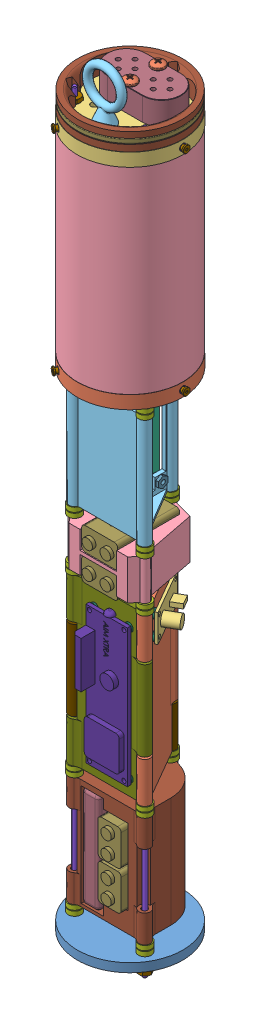
SolidWorks assembly S1B_Electronics_Bay, configuration Default. Lengths in mm.
Overall size (104.18 564.06 103.27).
130 component instances, 38 part files, 86 mates.
Components (placement in the parent):
- S1B_Electronics_Bay_Aft_Bulkhead-1: S1B_Electronics_Bay_Aft_Bulkhead [Default] at origin size (76.45 6.35 76.45)
- S1B_Electronics_Bay_Spacer_Aft_Bulkhead-1: S1B_Electronics_Bay_Spacer_Aft_Bulkhead [Default] at (0 353.8981 0) size (76.71 9.53 76.71)
- S1B_Electronics_Bay_Spacer_Forward_Bulkhead-1: S1B_Electronics_Bay_Spacer_Forward_Bulkhead [Default] at (0 506.2727 0) size (76.71 9.53 76.71)
- S1B_Fat_Bulkhead_Coupler-2: S1B_Fat_Bulkhead_Coupler [Default] at (0 363.4231 0) size (76.45 142.85 76.45)
- S1B_Electronics_Bay_3014T45_Steel Eyebolt with Shoulder - for Lifting-1: S1B_Electronics_Bay_3014T45_Steel Eyebolt with Shoulder - for Lifting [3014T45] at (0 539.6102 18.415) size (30.16 64.29 14.29)
- S1B_Electronics_Bay_90107A029_316 Stainless Steel Washer-1: S1B_Electronics_Bay_90107A029_316 Stainless Steel Washer [90107A029] at (0 505.1805 18.415) x (-1 0 0) z (0 0 -1) size (15.88 1.09 15.88)
- S1B_Electronics_Bay_95462A029_Medium-Strength Steel Hex Nut-1: S1B_Electronics_Bay_95462A029_Medium-Strength Steel Hex Nut [95462A029] at (0 502.4024 18.415) x (1 0 0) z (0 1 0) size (11.11 12.83 5.56)
- S1B_Electronics_Bay_98804A006_18-8 Stainless Steel Threaded Rod-1: S1B_Electronics_Bay_98804A006_18-8 Stainless Steel Threaded Rod [98804A006] at (0 257.975 -29.464) x (1 0 0) z (0 -1 0) size (3.17 3.17 534.7)
- S1B_Electronics_Bay_91841A006_18-8 Stainless Steel Hex Nut-1: S1B_Electronics_Bay_91841A006_18-8 Stainless Steel Hex Nut [91841A006] at (0 517.8218 -29.464) x (-1 0 0) z (0 0 -1) size (7.94 2.78 9.17)
- S1B_Electronics_Bay_90107A006_316 Stainless Steel Washer-1: S1B_Electronics_Bay_90107A006_316 Stainless Steel Washer [90107A006] at (0 515.7977 -29.464) size (7.14 0.64 7.14)
- S1B_Electronics_Bay_90107A006_316 Stainless Steel Washer-4: S1B_Electronics_Bay_90107A006_316 Stainless Steel Washer [90107A006] at (25.5166 515.7977 14.732) x (-0.5 0 0.866025) z (-0.866025 0 -0.5) size (7.14 0.64 7.14)
- S1B_Electronics_Bay_90107A006_316 Stainless Steel Washer-5: S1B_Electronics_Bay_90107A006_316 Stainless Steel Washer [90107A006] at (-25.5166 515.7977 14.732) x (-0.5 0 -0.866025) z (0.866025 0 -0.5) size (7.14 0.64 7.14)
- S1B_Electronics_Bay_91841A006_18-8 Stainless Steel Hex Nut-2: S1B_Electronics_Bay_91841A006_18-8 Stainless Steel Hex Nut [91841A006] at (25.5166 517.8218 14.732) x (0.5 0 -0.866025) z (0.866025 0 0.5) size (7.94 2.78 9.17)
- S1B_Electronics_Bay_91841A006_18-8 Stainless Steel Hex Nut-3: S1B_Electronics_Bay_91841A006_18-8 Stainless Steel Hex Nut [91841A006] at (-25.5166 517.8218 14.732) x (0.5 0 0.866025) z (-0.866025 0 0.5) size (7.94 2.78 9.17)
- S1B_Electronics_Bay_98804A006_18-8 Stainless Steel Threaded Rod-4: S1B_Electronics_Bay_98804A006_18-8 Stainless Steel Threaded Rod [98804A006] at (25.5166 257.975 14.732) x (-0.5 0 0.866025) z (0 -1 0) size (3.17 3.17 534.7)
- S1B_Electronics_Bay_98804A006_18-8 Stainless Steel Threaded Rod-5: S1B_Electronics_Bay_98804A006_18-8 Stainless Steel Threaded Rod [98804A006] at (-25.5166 257.975 14.732) x (-0.5 0 -0.866025) z (0 -1 0) size (3.17 3.17 534.7)
- S1B_Electronics_Bay_90107A006_316 Stainless Steel Washer-12: S1B_Electronics_Bay_90107A006_316 Stainless Steel Washer [90107A006] at (0 0 -29.464) x (1 0 0) z (0 0 -1) size (7.14 0.64 7.14)
- S1B_Electronics_Bay_91841A006_18-8 Stainless Steel Hex Nut-14: S1B_Electronics_Bay_91841A006_18-8 Stainless Steel Hex Nut [91841A006] at (0 -2.0241 -29.464) x (-1 0 0) z (0 0 1) size (7.94 2.78 9.17)
- S1B_Electronics_Bay_90107A006_316 Stainless Steel Washer-13: S1B_Electronics_Bay_90107A006_316 Stainless Steel Washer [90107A006] at (25.5166 0 14.732) x (-0.5 0 0.866025) z (0.866025 0 0.5) size (7.14 0.64 7.14)
- S1B_Electronics_Bay_90107A006_316 Stainless Steel Washer-14: S1B_Electronics_Bay_90107A006_316 Stainless Steel Washer [90107A006] at (-25.5166 0 14.732) x (-0.5 0 -0.866025) z (-0.866025 0 0.5) size (7.14 0.64 7.14)
- S1B_Electronics_Bay_91841A006_18-8 Stainless Steel Hex Nut-15: S1B_Electronics_Bay_91841A006_18-8 Stainless Steel Hex Nut [91841A006] at (25.5166 -2.0241 14.732) x (0.5 0 -0.866025) z (-0.866025 0 -0.5) size (7.94 2.78 9.17)
- S1B_Electronics_Bay_91841A006_18-8 Stainless Steel Hex Nut-16: S1B_Electronics_Bay_91841A006_18-8 Stainless Steel Hex Nut [91841A006] at (-25.5166 -2.0241 14.732) x (0.5 0 0.866025) z (0.866025 0 -0.5) size (7.94 2.78 9.17)
- S1B_Electronics_Bay_Avionics_Stack-1: S1B_Electronics_Bay_Avionics_Stack [Default] at (8.2928 -12.2914 -69.8691) size (104.18 344.14 103.27)
  - S1B_Flight_Power_Stack_Assy-1: S1B_Flight_Power_Stack_Assy [Default] at (-4.2933 16.5157 -11.6983) size (58.99 80 57.67)
    - S1B_Power_Stack-1: S1B_Power_Stack [Default] at (-4.1095 89.1616 81.6309) size (58.99 80 52.18)
    - S1B_9V Battery-1: S1B_9V Battery [Default] at (-5.5953 51.787 105.8736) x (0 0 -1) z (0 -1 0) size (47.57 16.87 26.11)
    - S1B_LiPo_A1-1: S1B_LiPo_A1 [Default] at (-22.7297 11.3191 64.2994) x (0 1 0) z (0 0 -1) size (72.97 12.27 33.73)
    - S1B_9V Battery-2: S1B_9V Battery [Default] at (-5.5953 23.6758 105.8736) x (0 0 -1) z (0 -1 0) size (47.57 16.87 26.11)
  - S1B_Fight_Computer_Stack_Assy-1: S1B_Fight_Computer_Stack_Assy [Default] at (37.1119 269.2904 8.8488) x (0.5 0 0.866025) z (0 -1 0) size (74.68 77.18 120)
    - S1B_6.86mm_Nut_3mm_Hole-7: S1B_6.86mm_Nut_3mm_Hole [Default] at (49.4605 62.5264 50.3494) x (0.433013 -0.75 0.5) z (-0.25 0.433013 0.866025) size (7.92 1.91 6.86)
    - S1B_6.86mm_Nut_3mm_Hole-10: S1B_6.86mm_Nut_3mm_Hole [Default] at (38.5881 85.168 145.066) x (-0.433013 0.75 -0.5) z (-0.25 0.433013 0.866025) size (7.92 1.91 6.86)
    - S1B_6.86mm_Nut_3mm_Hole-11: S1B_6.86mm_Nut_3mm_Hole [Default] at (36.9383 84.2155 50.3494) x (0.433013 -0.75 -0.5) z (0.25 -0.433013 0.866025) size (7.92 1.91 6.86)
    - S1B_6.86mm_Nut_3mm_Hole-12: S1B_6.86mm_Nut_3mm_Hole [Default] at (49.4605 62.5264 145.066) x (0.433013 -0.75 -0.5) z (0.25 -0.433013 0.866025) size (7.92 1.91 6.86)
    - S1B_Ruber_Washer_3mm-5: S1B_Ruber_Washer_3mm [Default] at (53.7083 64.9789 145.066) x (-0.5 0.866025 0) z (0 0 1) size (6 1.25 6)
    - S1B_Ruber_Washer_3mm-6: S1B_Ruber_Washer_3mm [Default] at (41.1861 86.668 145.066) x (-0.5 0.866025 0) z (0 0 1) size (6 1.25 6)
    - S1B_Ruber_Washer_3mm-7: S1B_Ruber_Washer_3mm [Default] at (53.7083 64.9789 50.3494) x (-0.5 0.866025 0) z (0 0 1) size (6 1.25 6)
    - S1B_Ruber_Washer_3mm-8: S1B_Ruber_Washer_3mm [Default] at (41.1861 86.668 50.3494) x (-0.5 0.866025 0) z (0 0 1) size (6 1.25 6)
    - S1B_Avionics_Stack - AIM-1: S1B_Avionics_Stack - AIM [Default] at (55.5493 84.6273 26.5774) x (-0.5 -0.866025 0) z (0 0 1) size (33.58 52.18 120)
    - S1B_AimXtra-1: S1B_AimXtra [Default] at (39.9161 88.8677 47.8094) x (0 0 1) z (-0.5 0.866025 0) size (102.34 16.13 30.12)
    - S1B_6.86mm_Nut_3mm_Hole-13: S1B_6.86mm_Nut_3mm_Hole [Default] at (13.2223 66.1787 125.5587) x (0.433013 0.75 -0.5) z (0.25 0.433013 0.866025) size (7.92 1.91 6.86)
    - S1B_6.86mm_Nut_3mm_Hole-14: S1B_6.86mm_Nut_3mm_Hole [Default] at (24.7223 86.0973 125.5587) x (0.433013 0.75 -0.5) z (0.25 0.433013 0.866025) size (7.92 1.91 6.86)
    - S1B_6.86mm_Nut_3mm_Hole-15: S1B_6.86mm_Nut_3mm_Hole [Default] at (13.2223 66.1787 69.0624) x (0.433013 0.75 0.5) z (-0.25 -0.433013 0.866025) size (7.92 1.91 6.86)
    - S1B_6.86mm_Nut_3mm_Hole-16: S1B_6.86mm_Nut_3mm_Hole [Default] at (24.7223 86.0973 67.5587) x (0.433013 0.75 -0.5) z (0.25 0.433013 0.866025) size (7.92 1.91 6.86)
    - S1B_Ruber_Washer_3mm-9: S1B_Ruber_Washer_3mm [Default] at (21.3404 88.0498 67.5587) x (0.5 0.866025 0) z (0 0 1) size (6 1.25 6)
    - S1B_Ruber_Washer_3mm-10: S1B_Ruber_Washer_3mm [Default] at (9.8404 68.1312 69.0624) x (0.5 0.866025 0) z (0 0 1) size (6 1.25 6)
    - S1B_Ruber_Washer_3mm-11: S1B_Ruber_Washer_3mm [Default] at (21.3404 88.0498 125.5587) x (0.5 0.866025 0) z (0 0 1) size (6 1.25 6)
    - S1B_Ruber_Washer_3mm-12: S1B_Ruber_Washer_3mm [Default] at (9.8404 68.1312 125.5587) x (0.5 0.866025 0) z (0 0 1) size (6 1.25 6)
    - S1B_Avionics_Stack-1: S1B_Avionics_Stack [Default] at (4.7361 84.6273 26.5774) size (33.58 52.18 120)
    - S1B_RBP2W-1: S1B_RBP2W [Default] at (13.9471 81.3442 101.7819) x (0 0 -1) z (0.5 0.866025 0) size (65 5.1 31.05)
    - S1B_6.86mm_Nut_3mm_Hole-17: S1B_6.86mm_Nut_3mm_Hole [Default] at (44.7248 57.1953 44.9616) x (-0.868623 0 -0.495473) z (-0.495473 0 0.868623) size (7.92 1.91 6.86)
    - S1B_6.86mm_Nut_3mm_Hole-18: S1B_6.86mm_Nut_3mm_Hole [Default] at (44.7248 57.1953 59.1316) x (-0.868623 0 -0.495473) z (-0.495473 0 0.868623) size (7.92 1.91 6.86)
    - S1B_6.86mm_Nut_3mm_Hole-19: S1B_6.86mm_Nut_3mm_Hole [Default] at (12.4948 57.1953 59.1316) x (-0.868623 0 -0.495473) z (-0.495473 0 0.868623) size (7.92 1.91 6.86)
    - S1B_6.86mm_Nut_3mm_Hole-20: S1B_6.86mm_Nut_3mm_Hole [Default] at (12.4948 57.1953 44.9616) x (-0.855922 0 -0.517105) z (-0.517105 0 0.855922) size (7.92 1.91 6.86)
    - S1B_Ruber_Washer_3mm-13: S1B_Ruber_Washer_3mm [Default] at (12.4948 52.0403 44.9616) size (6 1.25 6)
    - S1B_Ruber_Washer_3mm-14: S1B_Ruber_Washer_3mm [Default] at (44.7248 52.0403 44.9616) size (6 1.25 6)
    - S1B_Ruber_Washer_3mm-15: S1B_Ruber_Washer_3mm [Default] at (44.7248 52.0403 59.1316) size (6 1.25 6)
    - S1B_Ruber_Washer_3mm-16: S1B_Ruber_Washer_3mm [Default] at (12.4948 52.0403 59.1316) size (6 1.25 6)
    - S1B_Avionics_Stack - EasyMini-1: S1B_Avionics_Stack - EasyMini [Default] at (30.1427 40.6218 26.5774) x (-0.5 0.866025 0) z (0 0 1) size (33.58 52.18 120)
    - S1B_EZMINI-1: S1B_EZMINI [Default] at (28.7345 50.2403 46.2994) x (1 0 0) z (0 0 -1) size (38.23 12.5 21.18)
  - S1B_Sensor_Power_Stack_Assy-1: S1B_Sensor_Power_Stack_Assy [Default] at (-32.7742 223.4603 27.9192) size (57.8 36.27 57.54)
    - S1B_Sensor_Power_Stack-1: S1B_Sensor_Power_Stack [Default] at (24.3714 13.7485 42.0133) size (57.8 28.96 55.69)
    - S1B_9V Battery-1: S1B_9V Battery [Default] at (37.7064 32.0365 66.7275) x (0 0 -1) z (1 0 0) size (47.57 16.87 26.11)
    - S1B_9V Battery-2: S1B_9V Battery [Default] at (37.7064 12.6309 66.7275) x (0 0 -1) z (1 0 0) size (47.57 16.87 26.11)
  - S1B_Sensor_Stack_Assy-1: S1B_Sensor_Stack_Assy [Default] at (-68.238 266.8297 115.4931) x (-0.5 0 -0.866025) z (0.866025 0 -0.5) size (58.99 80 52.18)
    - S1B_Sensor_Stack_T_Mount_A2-1: S1B_Sensor_Stack_T_Mount_A2 [Default] at (9.5389 -1.0891 74.5991) size (58.99 80 52.18)
    - S1B_6.86mm_Nut_3mm_Hole-1: S1B_6.86mm_Nut_3mm_Hole [Default] at (6.8862 79.7859 74.7996) x (0.75 0.5 0.433013) z (0.433013 -0.866025 0.25) size (7.92 1.91 6.86)
    - S1B_Ruber_Washer_3mm-1: S1B_Ruber_Washer_3mm [Default] at (28.3048 79.7859 83.7015) x (0.75 -0.5 0.433013) z (0.433013 0.866025 0.25) size (6 1.25 6)
    - S1B_Ruber_Washer_3mm-2: S1B_Ruber_Washer_3mm [Default] at (8.3862 79.7859 72.2015) x (0.75 -0.5 0.433013) z (0.433013 0.866025 0.25) size (6 1.25 6)
    - S1B_Ruber_Washer_3mm-3: S1B_Ruber_Washer_3mm [Default] at (28.3048 18.0359 83.7015) x (0.75 -0.5 0.433013) z (0.433013 0.866025 0.25) size (6 1.25 6)
    - S1B_Ruber_Washer_3mm-4: S1B_Ruber_Washer_3mm [Default] at (8.3862 18.0359 72.2015) x (0.75 -0.5 0.433013) z (0.433013 0.866025 0.25) size (6 1.25 6)
    - S1B_6.86mm_Nut_3mm_Hole-3: S1B_6.86mm_Nut_3mm_Hole [Default] at (26.8048 18.0359 86.2996) x (0.75 0.5 0.433013) z (0.433013 -0.866025 0.25) size (7.92 1.91 6.86)
    - S1B_6.86mm_Nut_3mm_Hole-4: S1B_6.86mm_Nut_3mm_Hole [Default] at (6.8862 18.0359 74.7996) x (0.75 0.5 0.433013) z (0.433013 -0.866025 0.25) size (7.92 1.91 6.86)
    - S1B_6.86mm_Nut_3mm_Hole-2: S1B_6.86mm_Nut_3mm_Hole [Default] at (26.8048 79.7859 86.2996) x (0.75 0.5 0.433013) z (0.433013 -0.866025 0.25) size (7.92 1.91 6.86)
    - S1B_Sensor_PCB-1: S1B_Sensor_PCB [Default] at (32.9609 14.7859 82.637) x (0 1 0) z (0.866025 0 0.5) size (68.25 2 30)
  - S1B_Blue_Damper-1: S1B_Blue_Damper [Default] at (-33.8094 18.6414 84.6011) x (0 0 -1) z (1 0 0) size (9.3 7.04 9.3)
  - S1B_Blue_Damper-19: S1B_Blue_Damper [Default] at (-33.8094 105.6772 84.6011) size (9.3 7.04 9.3)
  - S1B_Blue_Damper-22: S1B_Blue_Damper [Default] at (-33.8094 232.713 84.6011) size (9.3 7.04 9.3)
  - S1B_Blue_Damper-25: S1B_Blue_Damper [Default] at (-33.8094 268.7048 84.6011) x (-1 0 0) z (0 0 -1) size (9.3 7.04 9.3)
  - S1B_Blue_Damper-28: S1B_Blue_Damper [Default] at (-33.8094 355.7406 84.6011) size (9.3 7.04 9.3)
  - S1B_Blue_Damper-29: S1B_Blue_Damper [Default] at (17.1065 355.7406 84.4952) x (-0.5 0 -0.866025) z (0.866025 0 -0.5) size (9.3 7.04 9.3)
  - S1B_Blue_Damper-30: S1B_Blue_Damper [Default] at (-8.4431 355.7406 40.4537) x (-0.5 0 0.866025) z (-0.866025 0 -0.5) size (9.3 7.04 9.3)
  - S1B_Blue_Damper-26: S1B_Blue_Damper [Default] at (17.1065 268.7048 84.4952) x (0.5 0 0.866025) z (-0.866025 0 0.5) size (9.3 7.04 9.3)
  - S1B_Blue_Damper-27: S1B_Blue_Damper [Default] at (-8.4431 268.7048 40.4537) x (0.5 0 -0.866025) z (0.866025 0 0.5) size (9.3 7.04 9.3)
  - S1B_Blue_Damper-23: S1B_Blue_Damper [Default] at (17.1065 232.713 84.4952) x (-0.5 0 -0.866025) z (0.866025 0 -0.5) size (9.3 7.04 9.3)
  - S1B_Blue_Damper-24: S1B_Blue_Damper [Default] at (-8.4431 232.713 40.4537) x (-0.5 0 0.866025) z (-0.866025 0 -0.5) size (9.3 7.04 9.3)
  - S1B_Blue_Damper-20: S1B_Blue_Damper [Default] at (17.1065 105.6772 84.4952) x (-0.5 0 -0.866025) z (0.866025 0 -0.5) size (9.3 7.04 9.3)
  - S1B_Blue_Damper-21: S1B_Blue_Damper [Default] at (-8.4431 105.6772 40.4537) x (-0.5 0 0.866025) z (-0.866025 0 -0.5) size (9.3 7.04 9.3)
  - S1B_Blue_Damper-17: S1B_Blue_Damper [Default] at (17.1065 18.6414 84.4952) x (-0.866025 0 0.5) z (-0.5 0 -0.866025) size (9.3 7.04 9.3)
  - S1B_Blue_Damper-18: S1B_Blue_Damper [Default] at (-8.4431 18.6414 40.4537) x (0.866025 0 0.5) z (-0.5 0 0.866025) size (9.3 7.04 9.3)
- S1B_Airframe_Threaded_Inserts_92394A113_18-8 Stainless Steel Screw-to-Expand Insert for Plastic-1: S1B_Airframe_Threaded_Inserts_92394A113_18-8 Stainless Steel Screw-to-Expand Insert for Plastic [92394A113] at (-17.5895 358.6606 -30.4659) x (0 -1 0) z (0.866025 0 -0.5) size (5.05 6.35 5.05)
- S1B_Airframe_Bolts_90357A120_Ultra-Low-Profile Socket Head Screw-1: S1B_Airframe_Bolts_90357A120_Ultra-Low-Profile Socket Head Screw [90357A120] at (-18.3483 358.6606 -31.7802) x (0.866025 0 -0.5) z (0.5 0 0.866025) size (5.08 5.08 9.2)
- S1B_Airframe_Threaded_Inserts_92394A113_18-8 Stainless Steel Screw-to-Expand Insert for Plastic-2: S1B_Airframe_Threaded_Inserts_92394A113_18-8 Stainless Steel Screw-to-Expand Insert for Plastic [92394A113] at (35.179 358.6606 0) x (0 -1 0) z (0 0 1) size (5.05 6.35 5.05)
- S1B_Airframe_Threaded_Inserts_92394A113_18-8 Stainless Steel Screw-to-Expand Insert for Plastic-6: S1B_Airframe_Threaded_Inserts_92394A113_18-8 Stainless Steel Screw-to-Expand Insert for Plastic [92394A113] at (-17.5895 358.6606 30.4659) x (0 -1 0) z (-0.866025 0 -0.5) size (5.05 6.35 5.05)
- S1B_Airframe_Bolts_90357A120_Ultra-Low-Profile Socket Head Screw-2: S1B_Airframe_Bolts_90357A120_Ultra-Low-Profile Socket Head Screw [90357A120] at (36.6966 358.6606 0) x (0 0 1) z (-1 0 0) size (5.08 5.08 9.2)
- S1B_Airframe_Bolts_90357A120_Ultra-Low-Profile Socket Head Screw-6: S1B_Airframe_Bolts_90357A120_Ultra-Low-Profile Socket Head Screw [90357A120] at (-18.3483 358.6606 31.7802) x (-0.866025 0 -0.5) z (0.5 0 -0.866025) size (5.08 5.08 9.2)
- S1B_Airframe_Bolts_90357A120_Ultra-Low-Profile Socket Head Screw-8: S1B_Airframe_Bolts_90357A120_Ultra-Low-Profile Socket Head Screw [90357A120] at (-18.3483 511.0606 -31.7802) x (0.866025 0 -0.5) z (0.5 0 0.866025) size (5.08 5.08 9.2)
- S1B_Airframe_Threaded_Inserts_92394A113_18-8 Stainless Steel Screw-to-Expand Insert for Plastic-8: S1B_Airframe_Threaded_Inserts_92394A113_18-8 Stainless Steel Screw-to-Expand Insert for Plastic [92394A113] at (-17.5895 511.0606 -30.4659) x (0 -1 0) z (0.866025 0 -0.5) size (5.05 6.35 5.05)
- S1B_Airframe_Threaded_Inserts_92394A113_18-8 Stainless Steel Screw-to-Expand Insert for Plastic-5: S1B_Airframe_Threaded_Inserts_92394A113_18-8 Stainless Steel Screw-to-Expand Insert for Plastic [92394A113] at (35.179 511.0606 0) x (0 -1 0) z (0 0 1) size (5.05 6.35 5.05)
- S1B_Airframe_Threaded_Inserts_92394A113_18-8 Stainless Steel Screw-to-Expand Insert for Plastic-7: S1B_Airframe_Threaded_Inserts_92394A113_18-8 Stainless Steel Screw-to-Expand Insert for Plastic [92394A113] at (-17.5895 511.0606 30.4659) x (0 -1 0) z (-0.866025 0 -0.5) size (5.05 6.35 5.05)
- S1B_Airframe_Bolts_90357A120_Ultra-Low-Profile Socket Head Screw-5: S1B_Airframe_Bolts_90357A120_Ultra-Low-Profile Socket Head Screw [90357A120] at (36.6966 511.0606 0) x (0 0 1) z (-1 0 0) size (5.08 5.08 9.2)
- S1B_Airframe_Bolts_90357A120_Ultra-Low-Profile Socket Head Screw-7: S1B_Airframe_Bolts_90357A120_Ultra-Low-Profile Socket Head Screw [90357A120] at (-18.3483 511.0606 31.7802) x (-0.866025 0 -0.5) z (0.5 0 -0.866025) size (5.08 5.08 9.2)
- S1B_Peregrine_DualPeregrine_Threaded_Inserts_92394A101_18-8 Stainless Steel Screw-to-Expand Insert for Plastic-1: S1B_Peregrine_DualPeregrine_Threaded_Inserts_92394A101_18-8 Stainless Steel Screw-to-Expand Insert for Plastic [92394A101] at (0 511.0352 0) x (-1 0 0) z (0 0 -1) size (6.65 9.53 6.65)
- S1B_Peregrine_DualPeregrine_Threaded_Inserts_92394A101_18-8 Stainless Steel Screw-to-Expand Insert for Plastic-2: S1B_Peregrine_DualPeregrine_Threaded_Inserts_92394A101_18-8 Stainless Steel Screw-to-Expand Insert for Plastic [92394A101] at (0 511.0352 -20.32) x (-1 0 0) z (0 0 -1) size (6.65 9.53 6.65)
- S1B_O_Ring_Seal_with_Captured_Nuts-1: S1B_O_Ring_Seal_with_Captured_Nuts [Default] at (0 515.7977 0) size (76.2 14.25 76.2)
- S1B_Electronics_Bay_90107A006_316 Stainless Steel Washer-9: S1B_Electronics_Bay_90107A006_316 Stainless Steel Washer [90107A006] at (0 353.2631 -29.464) size (7.14 0.64 7.14)
- S1B_Electronics_Bay_91841A006_18-8 Stainless Steel Hex Nut-10: S1B_Electronics_Bay_91841A006_18-8 Stainless Steel Hex Nut [91841A006] at (0 351.8741 -29.464) x (-1 0 0) z (0 0 -1) size (7.94 2.78 9.17)
- S1B_Electronics_Bay_91841A006_18-8 Stainless Steel Hex Nut-12: S1B_Electronics_Bay_91841A006_18-8 Stainless Steel Hex Nut [91841A006] at (25.5166 351.8741 14.732) x (0.5 0 -0.866025) z (0.866025 0 0.5) size (7.94 2.78 9.17)
- S1B_Electronics_Bay_91841A006_18-8 Stainless Steel Hex Nut-13: S1B_Electronics_Bay_91841A006_18-8 Stainless Steel Hex Nut [91841A006] at (-25.5166 351.8741 14.732) x (0.5 0 0.866025) z (-0.866025 0 0.5) size (7.94 2.78 9.17)
- S1B_Electronics_Bay_90107A006_316 Stainless Steel Washer-10: S1B_Electronics_Bay_90107A006_316 Stainless Steel Washer [90107A006] at (25.5166 353.2631 14.732) x (-0.5 0 0.866025) z (-0.866025 0 -0.5) size (7.14 0.64 7.14)
- S1B_Electronics_Bay_90107A006_316 Stainless Steel Washer-11: S1B_Electronics_Bay_90107A006_316 Stainless Steel Washer [90107A006] at (-25.5166 353.2631 14.732) x (-0.5 0 -0.866025) z (0.866025 0 -0.5) size (7.14 0.64 7.14)
- S1B_9452K159_Oil-Resistant Buna-N O-Ring-1: S1B_9452K159_Oil-Resistant Buna-N O-Ring [Default] at (0 520.4967 0) size (76.2 3.81 76.2)
- S1B_Electronics_Bay_91841A006_18-8 Stainless Steel Hex Nut-17: S1B_Electronics_Bay_91841A006_18-8 Stainless Steel Hex Nut [91841A006] at (0 -4.8022 -29.464) x (0 0 -1) z (-1 0 0) size (7.94 2.78 9.17)
- S1B_Electronics_Bay_91841A006_18-8 Stainless Steel Hex Nut-18: S1B_Electronics_Bay_91841A006_18-8 Stainless Steel Hex Nut [91841A006] at (25.5166 -4.8022 14.732) x (0.866025 0 0.5) z (0.5 0 -0.866025) size (7.94 2.78 9.17)
- S1B_Electronics_Bay_91841A006_18-8 Stainless Steel Hex Nut-19: S1B_Electronics_Bay_91841A006_18-8 Stainless Steel Hex Nut [91841A006] at (-25.5166 -4.8022 14.732) x (-0.866025 0 0.5) z (0.5 0 0.866025) size (7.94 2.78 9.17)
- S1B_Peregrine_Assembly-1: S1B_Peregrine_Assembly [Default] at (-12.7 515.7977 -10.16) size (53.34 129.45 29.79)
  - S1B_Peregrine_DualPeregrine_CO2_System_Cap-1: S1B_Peregrine_DualPeregrine_CO2_System_Cap [Default] at origin size (53.34 16.87 27.94)
  - S1B_Peregrine_CO2_System_Tube-1: S1B_Peregrine_CO2_System_Tube [Default] at origin size (23.62 104.52 23.62)
  - S1B_Peregrine_CO2_System_Tube-2: S1B_Peregrine_CO2_System_Tube [Default] at (25.4 0 0) size (23.62 104.52 23.62)
  - S1B_Peregrine_Capsule-2: S1B_Peregrine_Capsule [Default] at (25.4 -87.884 0) size (18.64 82.88 18.64)
  - S1B_Peregrine_Capsule-3: S1B_Peregrine_Capsule [Default] at (0 -87.884 0) size (18.64 82.88 18.64)
  - S1B_Peregrine_Charge_Cup-1: S1B_Peregrine_Charge_Cup [Default] at (25.4 -109.2708 0) size (18.85 16.36 18.85)
  - S1B_Peregrine_Charge_Cup-2: S1B_Peregrine_Charge_Cup [Default] at (0 -109.2708 0) size (18.85 16.36 18.85)
  - S1B_Peregrine_Lift_Piston-1: S1B_Peregrine_Lift_Piston [Default] at (25.4 -92.9132 0) size (20.08 9.25 20.08)
  - S1B_Peregrine_Lift_Piston-2: S1B_Peregrine_Lift_Piston [Default] at (0 -92.9132 0) size (20.08 9.25 20.08)
  - S1B_Peregrine_Alignment_Collar-1: S1B_Peregrine_Alignment_Collar [Default] at (25.4 -8.89 0) x (-1 0 0) z (0 0 1) size (18.8 9.7 18.8)
  - S1B_Peregrine_Alignment_Collar-2: S1B_Peregrine_Alignment_Collar [Default] at (0 -8.89 0) x (-1 0 0) z (0 0 1) size (18.8 9.7 18.8)
  - S1B_Peregrine_Spring-1: S1B_Peregrine_Spring [Default] at (25.4 -8.89 0) size (18.69 11.43 17.78)
  - S1B_Peregrine_Spring-2: S1B_Peregrine_Spring [Default] at (0 -8.89 0) size (18.69 11.43 17.78)
  - S1B_Peregrine_DualPeregrine_Mounting_Bolt_91772A247_Passivated 18-8 Stainless Steel Pan Head Phillips Screw-1: S1B_Peregrine_DualPeregrine_Mounting_Bolt_91772A247_Passivated 18-8 Stainless Steel Pan Head Phillips Screw [91772A247] at (12.7 -8.5344 -10.16) x (-1 0 0) z (0 1 0) size (9.47 9.47 28.89)
  - S1B_Peregrine_DualPeregrine_Mounting_Bolt_91772A247_Passivated 18-8 Stainless Steel Pan Head Phillips Screw-2: S1B_Peregrine_DualPeregrine_Mounting_Bolt_91772A247_Passivated 18-8 Stainless Steel Pan Head Phillips Screw [91772A247] at (12.7 -8.5344 10.16) x (1 0 0) z (0 1 0) size (9.47 9.47 28.89)
Mates (geometry in assembly coordinates):
- Coincident1: coincident aligned: line of S1A_Electronics_Bay_Aft_Bulkhead-1 through (6.985 0 6.6675) axis (0 0 -1)
- Parallel1: parallel aligned: plane of S1A_Electronics_Bay_Aft_Bulkhead-1 through (0 0 0) normal (0 0 1)
- Coincident3: coincident aligned: plane of S1A_Electronics_Bay_Aft_Bulkhead-1 through (0 0 0) normal (0 1 0)
- Coincident4: coincident aligned: line of S1B_Electronics_Bay_Spacer_Aft_Bulkhead-1 through (10.4775 0 363.8994) axis (0 0 -1)
- Distance1: distance = 324.993 mm anti-aligned: plane of S1A_Electronics_Bay_Aft_Bulkhead-1 through (0 6.35 0) normal (0 1 0); plane of S1A_Electronics_Bay_Spacer_Aft_Bulkhead-1 through (0 353.8981 0) normal (0 -1 0)
- Coincident5: coincident aligned: plane of S1B_Electronics_Bay_Spacer_Aft_Bulkhead-1 through (0 353.8981 0) normal (0 0 1)
- Parallel2: parallel aligned: plane of S1B_Electronics_Bay_Spacer_Forward_Bulkhead-1 through (0 506.2727 0) normal (0 0 1)
- Coincident7: coincident aligned: line of S1A_Fat_Bulkhead_Spacer-1 through (97.79 0 385.5089) axis (0 0 -1)
- Coincident8: coincident aligned: plane of S1A_Fat_Bulkhead_Spacer-1 through (0 292.1639 0) normal (0 0 1)
- Coincident9: coincident anti-aligned: plane of S1B_Electronics_Bay_Spacer_Aft_Bulkhead-1 through (0 363.4231 0) normal (0 1 0); plane of S1B_Fat_Bulkhead_Coupler-2 through (0 363.4231 0) normal (0 -1 0)
- Coincident10: coincident anti-aligned: line of S1B_Fat_Bulkhead_Coupler-2 through (157.1346 0 356.2806) axis (0 0 1)
- Parallel3: parallel aligned: plane of S1B_Fat_Bulkhead_Coupler-2 through (0 363.4231 0) normal (0 0 1)
- Coincident12: coincident anti-aligned: plane of S1B_Electronics_Bay_Spacer_Forward_Bulkhead-1 through (0 506.2727 0) normal (0 -1 0); plane of S1B_Fat_Bulkhead_Coupler-2 through (0 506.2727 0) normal (0 1 0)
- Coincident13: coincident aligned: plane of S1B_Electronics_Bay_Spacer_Forward_Bulkhead-1 through (0 515.7977 0) normal (0 1 0); plane of S1A_DualPeregrine_CO2_System-1 through (-12.7 515.7977 -10.16) normal (0 1 0)
- Coincident14: coincident aligned: plane of S1A_DualPeregrine_CO2_System-1 through (0 515.7977 -10.16) normal (1 0 0)
- Distance2: distance = 10.16 mm aligned: plane of S1A_DualPeregrine_CO2_System-1 through (-12.7 515.7977 -10.16) normal (0 0 1)
- Coincident15: coincident anti-aligned: plane of S1B_Electronics_Bay_Spacer_Forward_Bulkhead-1 through (0 515.7977 0) normal (0 1 0); plane of S1A_Electronics_Bay_3014T45_Steel Eyebolt with Shoulder - for Lifting-1 through (-6.4492 515.7977 18.415) normal (0 -1 0)
- Parallel4: parallel aligned: plane of S1A_Electronics_Bay_3014T45_Steel Eyebolt with Shoulder - for Lifting-1 through (0 539.6102 18.415) normal (0 0 1)
- Coincident16: coincident aligned: line of S1A_Electronics_Bay_3014T45_Steel Eyebolt with Shoulder - for Lifting-1 through (0 487.183 18.415) axis (0 1 0); line of S1A_Electronics_Bay_90107A029_316 Stainless Steel Washer-1 through (0 505.1259 18.415) axis (0 1 0)
- Coincident17: coincident anti-aligned: plane of S1B_Electronics_Bay_Spacer_Forward_Bulkhead-1 through (0 506.2727 0) normal (0 -1 0); plane of S1A_Electronics_Bay_90107A029_316 Stainless Steel Washer-1 through (0 506.2727 18.415) normal (0 1 0)
- Concentric2: concentric aligned: cylinder of S1B_Electronics_Bay_Spacer_Forward_Bulkhead-1 through (0 506.2727 18.415) axis (0 1 0) radius 4.1275; line of S1A_Electronics_Bay_3014T45_Steel Eyebolt with Shoulder - for Lifting-1 through (0 487.183 18.415) axis (0 1 0)
- Parallel5: parallel anti-aligned: plane of S1A_Electronics_Bay_90107A029_316 Stainless Steel Washer-1 through (0 505.1805 18.415) normal (0 0 -1)
- Coincident18: coincident anti-aligned: plane of S1A_Electronics_Bay_90107A029_316 Stainless Steel Washer-1 through (0 505.1805 18.415) normal (0 -1 0); plane of S1A_Electronics_Bay_95462A029_Medium-Strength Steel Hex Nut-1 through (-5.5563 505.1805 15.2071) normal (0 1 0)
- Coincident19: coincident anti-aligned: line of S1A_Electronics_Bay_3014T45_Steel Eyebolt with Shoulder - for Lifting-1 through (0 487.183 18.415) axis (0 1 0); line of S1A_Electronics_Bay_95462A029_Medium-Strength Steel Hex Nut-1 through (0 505.4583 18.415) axis (0 -1 0)
- Parallel6: parallel anti-aligned: plane of S1A_Electronics_Bay_95462A029_Medium-Strength Steel Hex Nut-1 through (0 502.4024 18.415) normal (0 0 -1)
- Coincident20: coincident aligned: line of S1A_O_Ring_Seal-1 through (13.97 0 532.7554) axis (0 0 -1)
- Coincident21: coincident anti-aligned: plane of S1B_Electronics_Bay_Spacer_Forward_Bulkhead-1 through (0 515.7977 0) normal (0 1 0); plane of S1B_O_Ring_Seal_with_Captured_Nuts-1 through (38.1 515.7977 0) normal (0 -1 0)
- Coincident22: coincident aligned: plane of S1A_O_Ring_Seal-1 through (0 519.4204 0) normal (0 0 1)
- Parallel8: parallel aligned: plane of S1B_Electronics_Bay_98804A006_18-8 Stainless Steel Threaded Rod-1 through (0 257.975 -29.464) normal (0 0 1)
- Parallel9: parallel aligned: plane of S1A_Electronics_Bay_98804A006_18-8 Stainless Steel Threaded Rod-2 through (25.5166 255.5748 14.732) normal (0 0 1)
- Coincident25: coincident aligned: plane of S1B_Electronics_Bay_98804A006_18-8 Stainless Steel Threaded Rod-1 through (0 525.3227 -27.8765) normal (0 1 0); plane of S1A_Electronics_Bay_98804A006_18-8 Stainless Steel Threaded Rod-2 through (25.5166 523.8496 16.3195) normal (0 1 0)
- Coincident26: coincident aligned: plane of S1A_Electronics_Bay_98804A006_18-8 Stainless Steel Threaded Rod-2 through (25.5166 523.8496 16.3195) normal (0 1 0); plane of S1A_Electronics_Bay_98804A006_18-8 Stainless Steel Threaded Rod-3 through (0 523.8496 -31.0515) normal (0 1 0)
- Parallel11: parallel anti-aligned: plane of S1A_Electronics_Bay_98804A006_18-8 Stainless Steel Threaded Rod-3 through (0 255.5748 -29.464) normal (0 0 -1)
- Coincident28: coincident anti-aligned: plane of S1B_Electronics_Bay_Spacer_Forward_Bulkhead-1 through (0 515.7977 0) normal (0 1 0); plane of S1A_Electronics_Bay_90107A006_316 Stainless Steel Washer-1 through (0 515.7977 -29.464) normal (0 -1 0)
- Parallel12: parallel aligned: plane of S1A_Electronics_Bay_90107A006_316 Stainless Steel Washer-1 through (0 515.7977 -29.464) normal (0 0 1)
- Coincident29: coincident anti-aligned: plane of S1A_Electronics_Bay_91841A006_18-8 Stainless Steel Hex Nut-1 through (3.9688 516.4327 -27.1726) normal (0 -1 0); plane of S1A_Electronics_Bay_90107A006_316 Stainless Steel Washer-1 through (0 516.4327 -29.464) normal (0 1 0)
- Parallel13: parallel anti-aligned: plane of S1A_Electronics_Bay_91841A006_18-8 Stainless Steel Hex Nut-1 through (0 517.8218 -29.464) normal (0 0 -1)
- Distance5: distance = 9.525 mm aligned: plane of S1B_Electronics_Bay_Spacer_Forward_Bulkhead-1 through (0 515.7977 0) normal (0 1 0); plane of S1A_Electronics_Bay_98804A006_18-8 Stainless Steel Threaded Rod-1 through (0 525.3227 -27.8765) normal (0 1 0)
- Concentric11: concentric aligned: cylinder of S1B_Electronics_Bay_98804A006_18-8 Stainless Steel Threaded Rod-5 through (-25.5166 -9.3727 14.732) axis (0 -1 0) radius 1.5875; cylinder of S1B_Electronics_Bay_Avionics_Stack-1/S1B_Sensor_Stack_Assy-1/S1B_Sensor_Stack_T_Mount_A2-1 through (-25.5166 343.4492 14.732) axis (0 -1 0) radius 2.0875
- Parallel14: parallel aligned: plane of S1B_Electronics_Bay_Avionics_Stack-1 through (8.2928 -12.2914 -69.8691) normal (0 0 1)
- Parallel15: parallel anti-aligned: plane of S1B_Airframe_Threaded_Inserts_92394A113_18-8 Stainless Steel Screw-to-Expand Insert for Plastic-1 through (-17.5895 358.6606 -30.4659) normal (0 -1 0)
- Concentric13: concentric aligned: cylinder of S1B_Electronics_Bay_Spacer_Aft_Bulkhead-1 through (-16.002 358.6606 -27.7163) axis (-0.5 0 -0.866025) radius 2.3749; line of S1B_Airframe_Threaded_Inserts_92394A113_18-8 Stainless Steel Screw-to-Expand Insert for Plastic-1 through (-15.8432 358.6606 -27.4413) axis (-0.5 0 -0.866025)
- Coincident31: coincident aligned: plane of S1B_Electronics_Bay_Spacer_Aft_Bulkhead-1 through (-19.177 353.8981 -33.2155) normal (-0.5 0 -0.866025); plane of S1B_Airframe_Threaded_Inserts_92394A113_18-8 Stainless Steel Screw-to-Expand Insert for Plastic-1 through (-19.177 358.6606 -33.2155) normal (-0.5 0 -0.866025)
- Concentric14: concentric aligned: cylinder of S1B_Electronics_Bay_Spacer_Aft_Bulkhead-1 through (-16.002 358.6606 -27.7163) axis (-0.5 0 -0.866025) radius 2.3749; line of S1B_Airframe_Bolts_90357A120_Ultra-Low-Profile Socket Head Screw-1 through (-15.8419 358.6606 -27.439) axis (-0.5 0 -0.866025)
- Parallel16: parallel aligned: plane of S1B_Airframe_Bolts_90357A120_Ultra-Low-Profile Socket Head Screw-1 through (-18.3483 358.6606 -31.7802) normal (0 1 0)
- Distance6: distance = 1.7272 mm anti-aligned: plane of S1A_Airframe_Threaded_Inserts_92394A113_18-8 Stainless Steel Screw-to-Expand Insert for Plastic-1 through (-19.177 358.6606 -33.2155) normal (-0.5 0 -0.866025); plane of S1A_Airframe_Bolts_90357A120_Ultra-Low-Profile Socket Head Screw-1 through (-20.0406 358.6606 -34.7113) normal (0.5 0 0.866025)
- Concentric15: concentric aligned: cylinder of S1B_Electronics_Bay_Spacer_Forward_Bulkhead-1 through (0 506.2727 0) axis (0 1 0) radius 3.175; line of S1A_DualPeregrine_Threaded_Inserts_92394A101_18-8 Stainless Steel Screw-to-Expand Insert for Plastic-1 through (10.4775 0 505.7965) axis (0 0 1)
- Coincident32: coincident aligned: plane of S1B_Electronics_Bay_Spacer_Forward_Bulkhead-1 through (0 515.7977 0) normal (0 1 0); plane of S1A_DualPeregrine_Threaded_Inserts_92394A101_18-8 Stainless Steel Screw-to-Expand Insert for Plastic-1 through (0 515.7977 0) normal (0 1 0)
- Parallel17: parallel anti-aligned: plane of S1A_DualPeregrine_Threaded_Inserts_92394A101_18-8 Stainless Steel Screw-to-Expand Insert for Plastic-1 through (0 511.0352 0) normal (0 0 -1)
- Concentric16: concentric aligned: cylinder of S1B_Electronics_Bay_Spacer_Forward_Bulkhead-1 through (0 506.2727 -20.32) axis (0 1 0) radius 3.175; line of S1A_DualPeregrine_Threaded_Inserts_92394A101_18-8 Stainless Steel Screw-to-Expand Insert for Plastic-2 through (0 505.7965 -20.32) axis (0 1 0)
- Coincident33: coincident aligned: plane of S1B_Electronics_Bay_Spacer_Forward_Bulkhead-1 through (0 515.7977 0) normal (0 1 0); plane of S1A_DualPeregrine_Threaded_Inserts_92394A101_18-8 Stainless Steel Screw-to-Expand Insert for Plastic-2 through (0 515.7977 -20.32) normal (0 1 0)
- Parallel18: parallel anti-aligned: plane of S1A_DualPeregrine_Threaded_Inserts_92394A101_18-8 Stainless Steel Screw-to-Expand Insert for Plastic-2 through (0 511.0352 -20.32) normal (0 0 -1)
- Concentric17: concentric aligned: cylinder of S1A_DualPeregrine_CO2_System-1 through (0 411.2767 0) axis (0 1 0) radius 2.286; line of S1A_DualPeregrine_Mounting_Bolt_91772A247_Passivated 18-8 Stainless Steel Pan Head Phillips Screw-1 through (31.7788 0 505.6454) axis (0 0 1)
- Coincident34: coincident anti-aligned: plane of S1A_DualPeregrine_CO2_System-1 through (-12.7 532.6633 -10.16) normal (0 1 0); plane of S1A_DualPeregrine_Mounting_Bolt_91772A247_Passivated 18-8 Stainless Steel Pan Head Phillips Screw-1 through (0 532.6633 0) normal (0 -1 0)
- Parallel19: parallel aligned: plane of S1A_DualPeregrine_Mounting_Bolt_91772A247_Passivated 18-8 Stainless Steel Pan Head Phillips Screw-1 through (0 507.2633 0) normal (0 0 1)
- Concentric18: concentric aligned: cylinder of S1A_DualPeregrine_CO2_System-1 through (0 411.2767 -20.32) axis (0 1 0) radius 2.286; line of S1A_DualPeregrine_Mounting_Bolt_91772A247_Passivated 18-8 Stainless Steel Pan Head Phillips Screw-2 through (0 505.6454 -20.32) axis (0 1 0)
- Coincident35: coincident anti-aligned: plane of S1A_DualPeregrine_CO2_System-1 through (-12.7 532.6633 -10.16) normal (0 1 0); plane of S1A_DualPeregrine_Mounting_Bolt_91772A247_Passivated 18-8 Stainless Steel Pan Head Phillips Screw-2 through (0 532.6633 -20.32) normal (0 -1 0)
- Parallel20: parallel anti-aligned: plane of S1A_DualPeregrine_Mounting_Bolt_91772A247_Passivated 18-8 Stainless Steel Pan Head Phillips Screw-2 through (0 507.2633 -20.32) normal (0 0 -1)
- Coincident44: coincident anti-aligned: plane of S1A_Electronics_Bay_Avionics_Stack-1/Blue_Boy-6 through (-23.002 350.485 14.732) normal (0 1 0); plane of S1A_Electronics_Bay_91841A006_18-8 Stainless Steel Hex Nut-10 through (3.9688 350.485 -27.1726) normal (0 -1 0)
- Coincident37: coincident anti-aligned: plane of S1A_Electronics_Bay_Aft_Bulkhead-1 through (0 6.35 0) normal (0 1 0); plane of S1A_Electronics_Bay_Avionics_Stack-1/Blue_Boy-1 through (-25.5166 6.35 12.2174) normal (0 -1 0)
- Coincident38: coincident anti-aligned: plane of S1B_Electronics_Bay_Spacer_Forward_Bulkhead-1 through (0 515.7977 0) normal (0 1 0); plane of S1B_O_Ring_Seal_with_Captured_Nuts-1 through (38.1 515.7977 0) normal (0 -1 0)
- Coincident39: coincident aligned: line of S1B_O_Ring_Seal_with_Captured_Nuts-1 through (13.97 0 529.1327) axis (0 0 -1)
- Parallel21: parallel aligned: plane of S1B_O_Ring_Seal_with_Captured_Nuts-1 through (0 515.7977 0) normal (1 0 0)
- Concentric19: concentric aligned: cylinder of S1B_Electronics_Bay_98804A006_18-8 Stainless Steel Threaded Rod-1 through (0 -9.3727 -29.464) axis (0 -1 0) radius 1.5875; cylinder of S1A_Electronics_Bay_91841A006_18-8 Stainless Steel Hex Nut-7 through (0 521.989 -29.464) axis (0 -1 0) radius 1.5875
- Coincident40: coincident anti-aligned: plane of S1A_Electronics_Bay_91841A006_18-8 Stainless Steel Hex Nut-1 through (3.9688 519.2109 -27.1726) normal (0 1 0); plane of S1A_Electronics_Bay_91841A006_18-8 Stainless Steel Hex Nut-7 through (2.2914 519.2109 -33.4327) normal (0 -1 0)
- Perpendicular1: perpendicular: plane of S1A_Electronics_Bay_91841A006_18-8 Stainless Steel Hex Nut-7 through (0 520.5999 -29.464) normal (-1 0 0)
- Concentric20: concentric anti-aligned: cylinder of S1B_Electronics_Bay_98804A006_18-8 Stainless Steel Threaded Rod-1 through (0 -9.3727 -29.464) axis (0 -1 0) radius 1.5875; cylinder of S1A_Electronics_Bay_90107A006_316 Stainless Steel Washer-9 through (0 353.2631 -29.464) axis (0 1 0) radius 1.7907
- Coincident41: coincident anti-aligned: plane of S1A_Electronics_Bay_91841A006_18-8 Stainless Steel Hex Nut-10 through (3.9688 350.485 -27.1726) normal (0 -1 0); plane of S1A_Electronics_Bay_91841A006_18-8 Stainless Steel Hex Nut-11 through (242.6657 760.6172 -245.1858) normal (0 1 0)
- Concentric21: concentric aligned: cylinder of S1B_Electronics_Bay_98804A006_18-8 Stainless Steel Threaded Rod-1 through (0 -9.3727 -29.464) axis (0 -1 0) radius 1.5875; cylinder of S1A_Electronics_Bay_91841A006_18-8 Stainless Steel Hex Nut-10 through (0 353.2631 -29.464) axis (0 -1 0) radius 1.5875
- Coincident42: coincident anti-aligned: plane of S1B_Electronics_Bay_Spacer_Aft_Bulkhead-1 through (0 353.8981 0) normal (0 -1 0); plane of S1A_Electronics_Bay_90107A006_316 Stainless Steel Washer-9 through (0 353.8981 -29.464) normal (0 1 0)
- Coincident43: coincident anti-aligned: plane of S1A_Electronics_Bay_90107A006_316 Stainless Steel Washer-9 through (0 353.2631 -29.464) normal (0 -1 0); plane of S1A_Electronics_Bay_91841A006_18-8 Stainless Steel Hex Nut-10 through (3.9688 353.2631 -27.1726) normal (0 1 0)
- Parallel23: parallel aligned: plane of S1A_Electronics_Bay_90107A006_316 Stainless Steel Washer-9 through (0 353.2631 -29.464) normal (0 0 1)
- Parallel24: parallel anti-aligned: plane of S1A_Electronics_Bay_91841A006_18-8 Stainless Steel Hex Nut-10 through (0 351.8741 -29.464) normal (0 0 -1)
- Coincident45: coincident anti-aligned: line of S1A_O_Ring-1 through (110 0 465.4967) axis (0 0 1)
- Coincident46: coincident anti-aligned: plane of S1B_O_Ring_Seal_with_Captured_Nuts-1 through (38.1 524.3067 0) normal (0 -1 0); plane of S1A_O_Ring-1 through (35.179 524.3067 0) normal (0 1 0)
- Parallel25: parallel aligned: plane of S1A_O_Ring-1 through (0 520.4967 0) normal (0 0 1)
- Coincident47: coincident aligned: line of S1B_Electronics_Bay_Spacer_Forward_Bulkhead-1 through (10.4775 0 516.274) axis (0 0 -1)
- Concentric22: concentric anti-aligned: cylinder of S1B_Electronics_Bay_Spacer_Forward_Bulkhead-1 through (0 506.2727 -29.464) axis (0 1 0) radius 1.651; cylinder of S1B_Electronics_Bay_98804A006_18-8 Stainless Steel Threaded Rod-1 through (0 -9.3727 -29.464) axis (0 -1 0) radius 1.5875
- Concentric23: concentric aligned: cylinder of S1B_Electronics_Bay_98804A006_18-8 Stainless Steel Threaded Rod-1 through (0 -9.3727 -29.464) axis (0 -1 0) radius 1.5875; cylinder of S1B_Electronics_Bay_91841A006_18-8 Stainless Steel Hex Nut-1 through (0 519.2109 -29.464) axis (0 -1 0) radius 1.5875
- Concentric24: concentric anti-aligned: cylinder of S1B_Electronics_Bay_98804A006_18-8 Stainless Steel Threaded Rod-1 through (0 -9.3727 -29.464) axis (0 -1 0) radius 1.5875; cylinder of S1B_Electronics_Bay_90107A006_316 Stainless Steel Washer-1 through (0 515.7977 -29.464) axis (0 1 0) radius 1.7907
- Concentric25: concentric anti-aligned: cylinder of S1B_Electronics_Bay_98804A006_18-8 Stainless Steel Threaded Rod-1 through (0 -9.3727 -29.464) axis (0 -1 0) radius 1.5875; cylinder of S1B_Electronics_Bay_91841A006_18-8 Stainless Steel Hex Nut-17 through (0 -6.1913 -29.464) axis (0 1 0) radius 1.5875
- Coincident48: coincident anti-aligned: plane of S1B_Electronics_Bay_91841A006_18-8 Stainless Steel Hex Nut-14 through (3.9688 -3.4131 -31.7554) normal (0 -1 0); plane of S1B_Electronics_Bay_91841A006_18-8 Stainless Steel Hex Nut-17 through (2.2914 -3.4131 -25.4953) normal (0 1 0)
- Parallel26: parallel aligned: plane of S1B_Electronics_Bay_91841A006_18-8 Stainless Steel Hex Nut-14 through (0 -2.0241 -29.464) normal (-1 0 0); plane of S1B_Electronics_Bay_91841A006_18-8 Stainless Steel Hex Nut-17 through (0 -4.8022 -29.464) normal (-1 0 0)
- Coincident49: coincident anti-aligned: plane of S1B_Electronics_Bay_Spacer_Forward_Bulkhead-1 through (0 515.7977 0) normal (0 1 0); plane of S1B_Peregrine_Assembly-1/S1B_Peregrine_DualPeregrine_CO2_System_Cap-1 through (-12.7 515.7977 -10.16) normal (0 -1 0)
- Concentric26: concentric aligned: cylinder of S1B_Electronics_Bay_Spacer_Forward_Bulkhead-1 through (-12.7 506.2727 -10.16) axis (0 1 0) radius 11.8745; cylinder of S1B_Peregrine_Assembly-1/S1B_Peregrine_CO2_System_Tube-1 through (-12.7 411.2767 -10.16) axis (0 1 0) radius 11.811
- Parallel27: parallel aligned: plane of S1B_Peregrine_Assembly-1 through (-12.7 515.7977 -10.16) normal (0 0 1)
